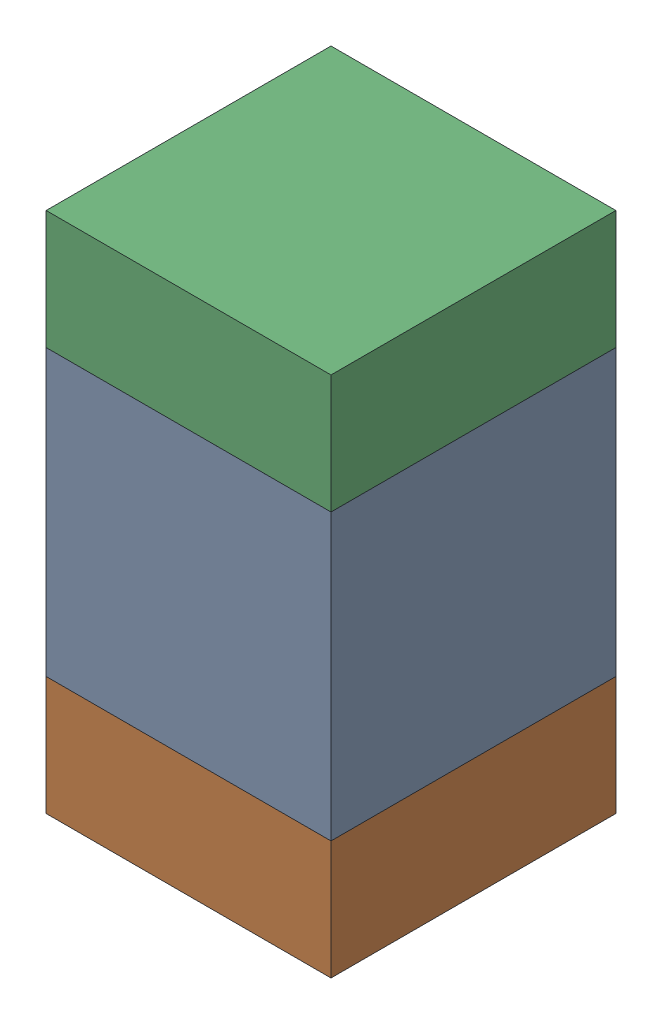
SolidWorks assembly C114_2PCB, configuration Default. Lengths in mm.
Overall size (0.6 1.1 0.6).
6 component instances, 2 part files, 0 mates.
Components (placement in the parent):
- 761606048-1: 761606048 [Default] at (116.1 99.4 0) size (0.6 0.6 0.6)
  - Extruded_9-1: Extruded_9 [Default] at origin size (0.6 0.6 0.6)
- 854785296-1: 854785296 [Default] at (116.1 98.975 0) size (0.6 0.25 0.6)
  - Extruded_10-1: Extruded_10 [Default] at origin size (0.6 0.25 0.6)
- 854785296-2: 854785296 [Default] at (116.1 99.825 0) size (0.6 0.25 0.6)
  - Extruded_10-1: Extruded_10 [Default] at origin size (0.6 0.25 0.6)
